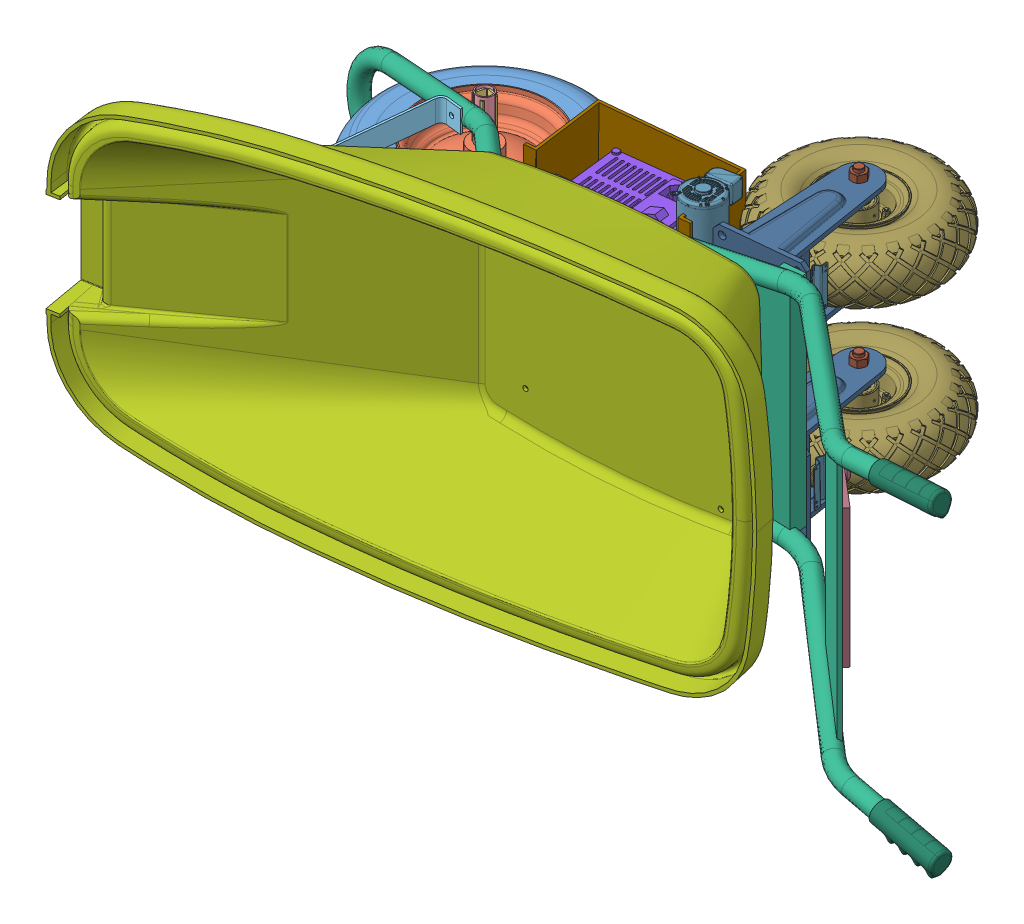
SolidWorks assembly Wheelbarrow model, configuration Default. Lengths in mm.
Overall size (1531.24 691.43 829.46).
22 component instances, 15 part files, 8 mates.
Components (placement in the parent):
- NZ tyre 1[Tyre]-1: NZ tyre 1[Tyre] [Default] x (1 0 0) z (0 0 -1) size (396 106.04 396)
- Hub-1: Hub [Default] x (1 0 0) z (0 0 -1) size (228 119.96 228)
- Sq.tubes-1: Sq.tubes [Default] x (1 0 0) z (0 0 -1) size (28.91 250 28.91)
- Axle[Part1]-1: Axle[Part1] [Default] x (1 0 0) z (0 0 -1) size (30 260 30)
- Supports-1: Supports [Default] x (0.995323 0 -0.096599) z (-0.096599 0 -0.995323) size (133.33 261.6 320.38)
- Handles actual[handle tube]-1: Handles actual[handle tube] [Default] x (0.995323 0 -0.096599) z (-0.096599 0 -0.995323) size (1406.7 588.08 569.12)
- Tray A1[Part1]-1: Tray A1[Part1] [Default] x (0.995323 0 -0.096599) z (-0.096599 0 -0.995323) size (1106.06 631.8 318.17)
- 29V_10A_charger_module-1: 29V_10A_charger_module [Default] at (333.5861 -14.7688 53.5565) x (0 -1 0) z (0.993474 0 -0.11406) size (406.8 129.6 181.2)
- battery case-1: battery case [Default] at (222.3202 218.2582 129.9209) x (-0.024537 -0.999649 -0.010039) z (-0.992274 0.023132 0.121893) size (400 135.8 270.63)
- wheel tyre-1: wheel tyre [Default] at (654.3802 -156.1933 68.7278) x (0 -1 0) z (-0.995323 0 0.096599) size (338.77 428.04 360.2)
  - âèëêà-1: âèëêà [Default] at (0 -10.0516 84.0306) x (1 0 0) z (0 -0.430421 0.902628) size (155 250.69 193.76)
  - â³ñü-1: â³ñü [Default] at (0 -205.5 85) size (170 30 30)
  - êîëåñî-1: êîëåñî [Default] at (0 -205.5 85) x (-1 0 0) z (0 0 -1) size (338.77 428.04 355.07)
- wheel tyre-2: wheel tyre [Default] at (654.3802 133.8067 68.7278) x (0 -1 0) z (-0.995323 0 0.096599) size (338.77 428.04 360.2)
  - âèëêà-1: âèëêà [Default] at (0 -10.0516 84.0306) x (1 0 0) z (0 -0.430421 0.902628) size (155 250.69 193.76)
  - â³ñü-1: â³ñü [Default] at (0 -205.5 85) size (170 30 30)
  - êîëåñî-1: êîëåñî [Default] at (0 -205.5 85) x (-1 0 0) z (0 0 -1) size (338.77 428.04 355.07)
- control panel q-1: control panel q [Default] at (919.4928 3.213 280.5204) x (0 1 0) z (0.648873 0 -0.760897) size (250 150 20)
- DC motor-1: DC motor [Default] at (454.4019 -172.8905 37.5987) x (0.016371 0.999256 0.034909) z (0.166031 -0.037146 0.985421) size (145.75 217.38 116.28)
- DC motor-2: DC motor [Default] at (461.6889 174.5208 80.8483) x (0.016371 -0.999256 0.034909) z (-0.166031 -0.037146 -0.985421) size (145.75 217.38 116.28)
- Grip-1: Grip [Default] at (1093.2802 -265.4706 376.5864) x (0.987595 -0.136863 0.076974) z (-0.14888 -0.971965 0.181983) size (122.43 38.1 52.29)
- Grip-2: Grip [Default] at (1092.3189 265.3374 376.5115) x (0.987595 0.136863 0.076974) z (0.152494 -0.952851 -0.262336) size (122.43 38.1 52.29)
Mates (geometry in assembly coordinates):
- Parallel7: parallel anti-aligned: line of Tray A1[Part1]-1 through (163.1585 166.6944 158.1113) axis (0 -1 0); line of 29V_10A_charger_module-1 through (250.4582 -183.3688 118.5623) axis (0 1 0)
- Coincident10: coincident anti-aligned: plane of Handles actual[handle tube]-1 through (12.2681 0 126.4061) normal (-0.096599 0 -0.995323); plane of wheel tyre-1/âèëêà-1 through (570.2964 -156.1933 72.2479) normal (0.096599 0 0.995323)
- Coincident11: coincident anti-aligned: line of Handles actual[handle tube]-1 through (647.434 200.0562 64.7615) axis (0 -1 0); line of wheel tyre-1/âèëêà-1 through (647.434 -223.6933 64.7615) axis (0 1 0)
- Coincident13: coincident anti-aligned: plane of Handles actual[handle tube]-1 through (248.6392 0 -291.5655) normal (0.648873 0 -0.760897); plane of _C;LB(2)-1/eBom-prt0-1 through (948.7109 -96.8738 305.4368) normal (-0.648873 0 0.760897)
- Coincident14: coincident anti-aligned: line of Handles actual[handle tube]-1 through (976.5601 -238.5482 329.1858) axis (0 1 0); line of control panel q-1 through (976.5601 128.213 329.1858) axis (0 -1 0)
- Coincident15: coincident anti-aligned: plane of Handles actual[handle tube]-1 through (248.6392 0 -291.5655) normal (0.648873 0 -0.760897); plane of control panel q-1 through (919.4928 3.213 280.5204) normal (-0.648873 0 0.760897)
- Concentric1: concentric anti-aligned: cylinder of Handles actual[handle tube]-1 through (1034.7593 -257.3606 372.0253) axis (0.987595 -0.136863 0.076974) radius 15.6; cylinder of Grip-1 through (1213.6878 -282.1568 385.9711) axis (-0.987595 0.136863 -0.076974) radius 15.24
- Concentric2: concentric anti-aligned: cylinder of Handles actual[handle tube]-1 through (1034.7593 257.3606 372.0253) axis (0.987595 0.136863 0.076974) radius 15.6; cylinder of Grip-2 through (1212.7265 282.0236 385.8962) axis (-0.987595 -0.136863 -0.076974) radius 15.24
